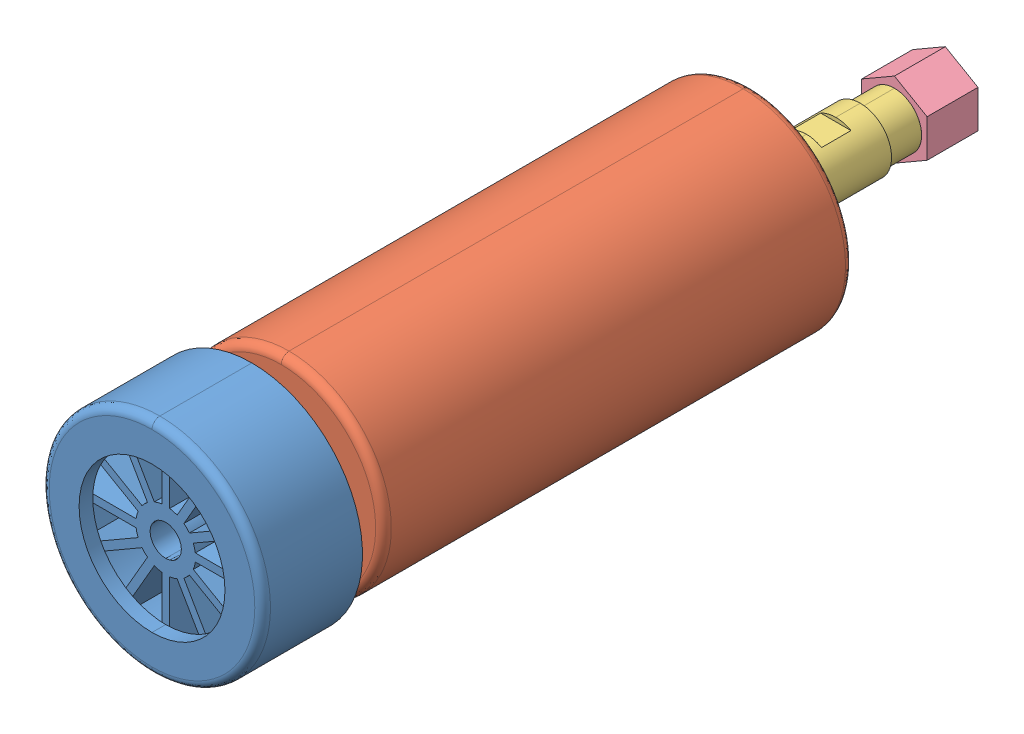
SolidWorks assembly SpindleAsm, configuration Default. Lengths in mm.
Overall size (56.5 56.5 202.62).
10 component instances, 4 part files, 0 mates.
Components (placement in the parent):
- SpindleAsm.STEP-1: SpindleAsm.STEP [Default] at origin size (56.5 56.5 202.62)
  - X-Y-Z-Assembled.stp.STEP-1: X-Y-Z-Assembled.stp.STEP [Default] at origin size (56.5 56.5 202.62)
    - X-Z-Assembled.stp.STEP-1: X-Z-Assembled.stp.STEP [Default] at (-102.9675 114.5006 640.1004) size (56.5 56.5 202.62)
      - z-test-assembly.stp.STEP-1: z-test-assembly.stp.STEP [Default] at (702.9675 35.4994 -640.1004) x (1 0 0) z (0 0 -1) size (56.5 56.5 202.62)
        - dustshoe.stp.STEP-1: dustshoe.stp.STEP [Default] at (250 0 340) x (0 1 0) z (-1 0 0) size (56.5 202.62 56.5)
          - spindle.stp.STEP-1: spindle.stp.STEP [Default] x (1 0 0) z (0 1 0) size (56.5 56.5 202.62)
            - fan.stp.STEP-1: fan.stp.STEP [Default] at (466.4996 -665.9873 822.7999) size (56.5 56.5 25.5)
            - motor.stp.STEP-1: motor.stp.STEP [Default] at (466.4996 -665.9873 822.7999) size (52.25 52.25 132.6)
            - Component3_1.stp.STEP-1: Component3_1.stp.STEP [Default] at (466.4996 -665.9873 822.7999) size (16 16 28.72)
            - Component4.stp.STEP-1: Component4.stp.STEP [Default] at (466.4996 -665.9873 822.7999) size (19.28 16.7 13)
